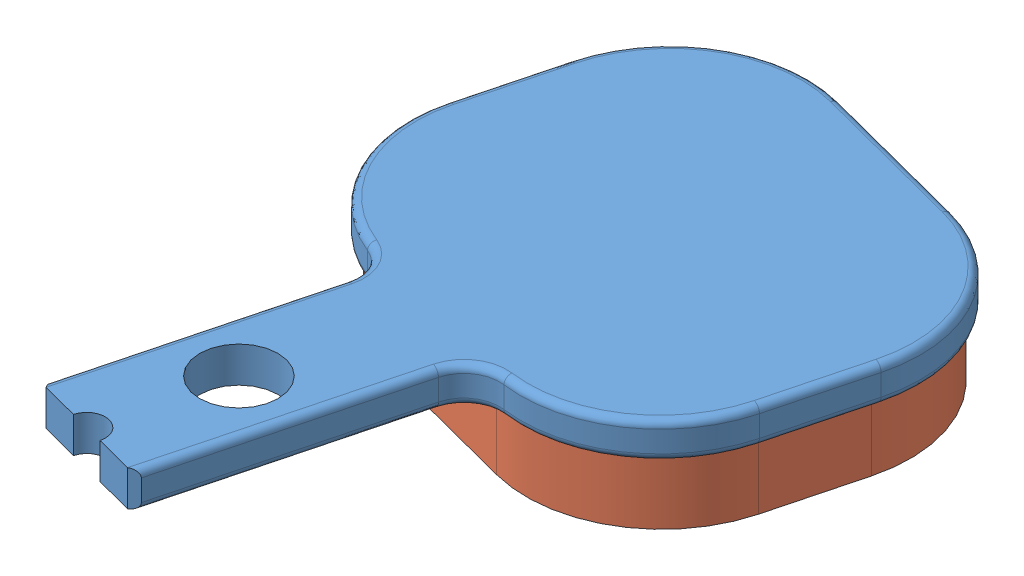
SolidWorks assembly PUTM-S-SF-BS-waBromskloss_31, configuration Domyślna. Lengths in mm.
Overall size (31.91 7 47.71).
2 component instances, 2 part files, 0 mates.
Components (placement in the parent):
- PUTM-S-SF-BS-waKlossplatta_301-1: PUTM-S-SF-BS-waKlossplatta_301 [Domyślna] at (35.6266 20.0867 -145.2058) size (31.91 2.5 47.71)
- PUTM-S-SF-BS-waKlossbelgg_311-1: PUTM-S-SF-BS-waKlossbelgg_311 [Domyślna] at (35.6266 20.0867 -145.2058) size (30.8 4.5 27.94)
